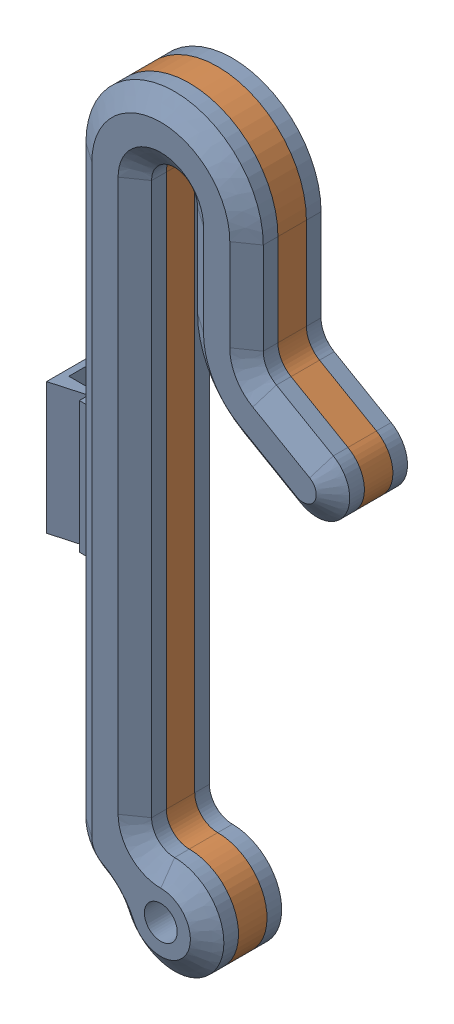
SolidWorks assembly Chain hook, configuration Default. Lengths in mm.
Overall size (58.62 147.32 16.51).
2 component instances, 2 part files, 3 mates.
Components (placement in the parent):
- Chain hook - plastic-1: Chain hook - plastic [Metal] at (-6.4289 -36.7296 28.346) size (58.62 147.32 16.51)
- Chain hook - Metal-1: Chain hook - Metal [Default] at (-6.4289 -36.7296 28.346) size (51 147.32 5.5)
Mates (geometry in assembly coordinates):
- Coincident1: coincident anti-aligned: plane of Chain hook - plastic-1 through (-6.4289 -36.7296 39.3527) normal (0 0 -1); plane of Chain hook - Metal-1 through (-6.4289 -36.7296 39.3527) normal (0 0 1)
- Coincident2: coincident anti-aligned: circle of Chain hook - plastic-1; cylinder of Chain hook - Metal-1 through (-6.4289 -36.7296 44.856) axis (0 0 -1) radius 3.175
- Concentric1: concentric aligned: cylinder of Chain hook - plastic-1 through (21.0796 49.8918 44.856) axis (0 0 -1) radius 6.35; cylinder of Chain hook - Metal-1 through (21.0796 49.8918 44.856) axis (0 0 -1) radius 6.35
